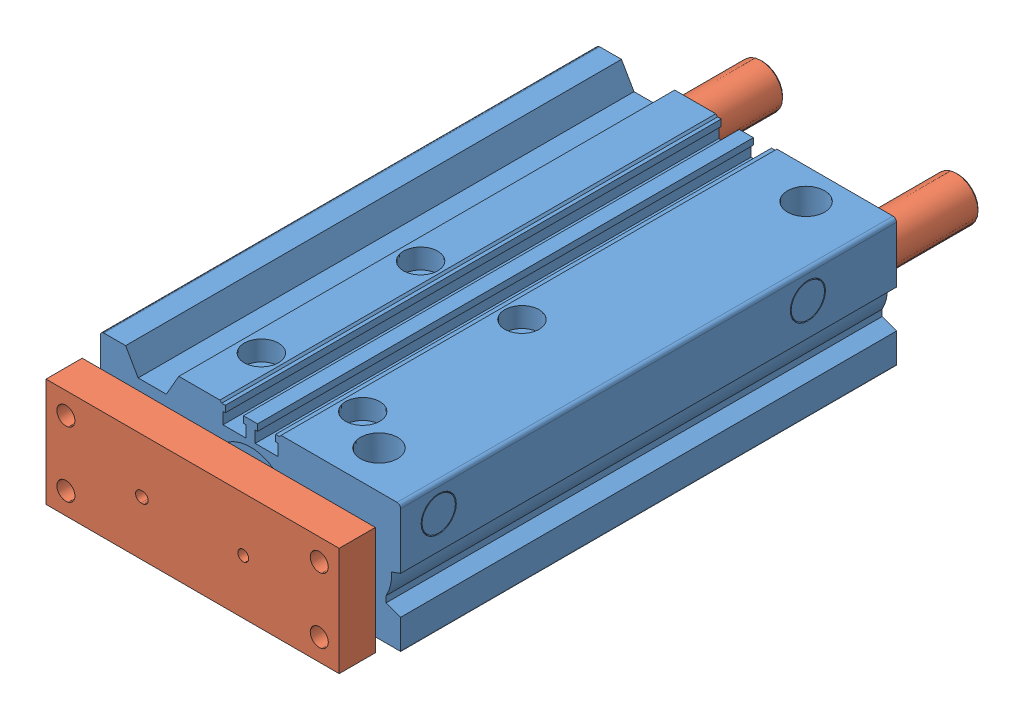
SolidWorks assembly CYLINDER ASSEMBLY, configuration MGPM20N-100. Lengths in mm.
Overall size (83 36 184.5).
2 component instances, 2 part files, 3 mates.
Components (placement in the parent):
- 5321-31 SMC MGPM20N-100_MGPTube-1: 5321-31 SMC MGPM20N-100_MGPTube [20M] at origin size (83 36 137)
- 5321-31 SMC MGPM20N-100_MGPRod-1: 5321-31 SMC MGPM20N-100_MGPRod [20M] at (0 0 -52.5) size (81 30 184.5)
Mates (geometry in assembly coordinates):
- Concentric1: concentric: cylinder of 5321-31 SMC MGPM20N-100_MGPTube-1 through (0 0 -14.2836) axis (0 0 1) radius 5.05; cylinder of 5321-31 SMC MGPM20N-100_MGPRod-1 through (0 0 88.6421) axis (0 0 -1) radius 5
- Parallel1: parallel: plane of 5321-31 SMC MGPM20N-100_MGPRod-1 through (0 0 -52.5) normal (0 1 0); plane of assembly through (0 0 0) normal (0 1 0)
- LimitDistance1: limit distance = 6 mm: plane of 5321-31 SMC MGPM20N-100_MGPTube-1 through (0 0 68.5) normal (0 0 1); plane of 5321-31 SMC MGPM20N-100_MGPRod-1 through (-40.5 -15 74.5) normal (0 0 -1)
